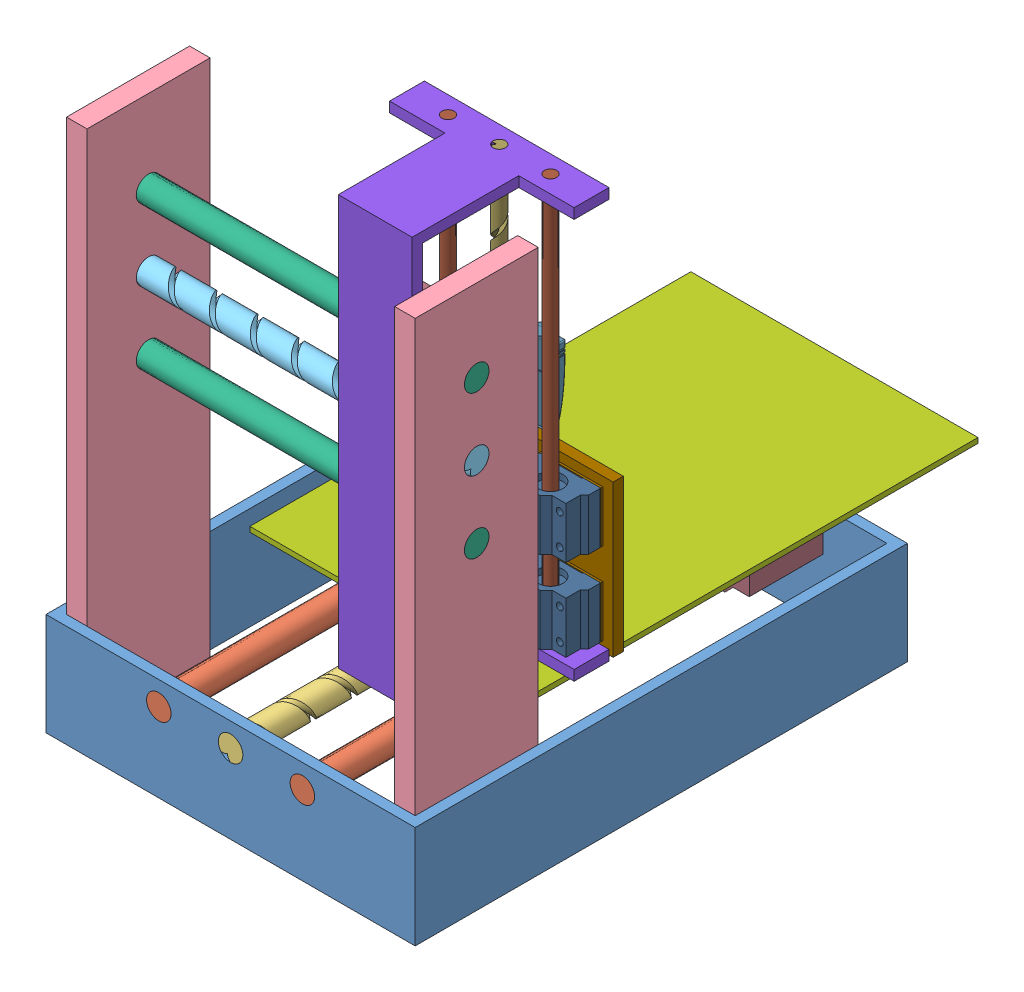
SolidWorks assembly INK Machine 2022, configuration Predeterminado. Lengths in mm.
Overall size (1205 1285 1203.26).
24 component instances, 14 part files, 60 mates.
Components (placement in the parent):
- BASE-1: BASE [Predeterminado] at (-71.4442 -39.2888 240) size (180 50 240)
- barra-1: barra [Predeterminado] at (-106.4442 -0.7888 120) x (-0.034704 -0.999398 0) z (0 0 1) size (12 12 240)
- barra-2: barra [Predeterminado] at (-36.4442 -0.7888 120) size (12 12 240)
- tornillo-1: tornillo [Predeterminado] at (-71.4442 -0.7888 60) x (-0.45507 -0.890456 0) z (0 0 1) size (12.31 12.31 1203.26)
- Viga superior-1: Viga superior [Predeterminado] at (13.5558 90.7112 325) x (0 0 1) z (-1 0 0) size (60 260 10)
- Viga superior-2: Viga superior [Predeterminado] at (-156.4442 90.7112 325) x (0 0 -1) z (1 0 0) size (60 260 10)
- tornillo2-1: tornillo2 [Predeterminado] at (13.5558 145.7112 325) x (0 0.604417 -0.796668) z (-1 0 0) size (12.31 12.31 1202.49)
- barra2-1: barra2 [Predeterminado] at (13.5558 180.7112 325) x (0 0.764966 -0.644071) z (-1 0 0) size (12 12 170)
- barra2-2: barra2 [Predeterminado] at (13.5558 110.7112 325) x (0 0.924225 0.381849) z (-1 0 0) size (12 12 170)
- cama-1: cama [Predeterminado] at (-71.4442 15.7112 143.0872) size (140 3.5 215)
- Caja superior-5: Caja superior [Predeterminado] at (-14.4442 145.7112 341.5) x (1 0 0) z (0 0 -1) size (90 200 69)
- CAMA SUPERIOR-1: CAMA SUPERIOR [Predeterminado] at (-14.4442 83.3129 275.5) x (-1 0 0) z (0 0 -1) size (90 74 6)
- SCS 6UU.stp-1: SCS 6UU.stp [Predeterminado] at (10.5558 90.8129 315) x (1 0 0) z (0 1 0) size (30 18 25)
- SCS 6UU.stp-2: SCS 6UU.stp [Predeterminado] at (10.5558 50.8129 315) x (1 0 0) z (0 1 0) size (30 18 25)
- SCS 6UU.stp-3: SCS 6UU.stp [Predeterminado] at (-39.4442 50.8129 315) x (1 0 0) z (0 1 0) size (30 18 25)
- SCS 6UU.stp-4: SCS 6UU.stp [Predeterminado] at (-39.4442 90.8129 315) x (1 0 0) z (0 1 0) size (30 18 25)
- barra3-1: barra3 [Predeterminado] at (-39.4442 45.7112 286) size (6 200 6)
- barra3-2: barra3 [Predeterminado] at (10.5558 45.7112 286) size (6 200 6)
- tornillo3-1: tornillo3 [Predeterminado] at (-14.4442 245.7112 286) x (-0.818193 0 0.574943) z (0 -1 0) size (6.16 6.16 1202.67)
- SCS12UU.stp-16: SCS12UU.stp [Predeterminado] at (-36.4442 -159.7888 125.0872) size (42 28 36)
- SCS12UU.stp-17: SCS12UU.stp [Predeterminado] at (-106.4442 -159.7888 125.0872) size (42 28 36)
- SCS12UU.stp-18: SCS12UU.stp [Predeterminado] at (3.5558 180.7112 166) x (0 -1 0) z (-1 0 0) size (42 28 36)
- SCS12UU.stp-19: SCS12UU.stp [Predeterminado] at (3.5558 110.7112 166) x (0 -1 0) z (-1 0 0) size (42 28 36)
- Reklaampastakas 1.step-2: Reklaampastakas 1.step [Predeterminado] at (-14.4442 32.6629 264.65) size (20 138.6 10.7)
Mates (geometry in assembly coordinates):
- Coincidente1: coincident aligned: plane of BASE-1 through (-161.4442 10.7112 360) normal (0 0 1); plane of tornillo-1 through (-71.4442 -0.7888 360) normal (0 0 1)
- Concéntrica7: concentric aligned: circle of BASE-1; circle of tornillo-1
- Coincidente3: coincident aligned: plane of BASE-1 through (-161.4442 10.7112 360) normal (0 0 1); plane of barra-1 through (-106.4442 -0.7888 360) normal (0 0 1)
- Concéntrica3: concentric aligned: circle of BASE-1; circle of barra-1
- Concéntrica4: concentric aligned: circle of BASE-1; circle of barra-2
- Coincidente6: coincident anti-aligned: plane of BASE-1 through (-156.4442 10.7112 125) normal (1 0 0); plane of Viga superior-2 through (-156.4442 90.7112 325) normal (-1 0 0)
- Coincidente7: coincident anti-aligned: plane of BASE-1 through (-156.4442 10.7112 355) normal (0 0 -1); plane of Viga superior-2 through (-146.4442 220.7112 355) normal (0 0 1)
- Coincidente8: coincident aligned: plane of BASE-1 through (-71.4442 -39.2888 240) normal (0 -1 0); plane of Viga superior-2 through (-146.4442 -39.2888 355) normal (0 -1 0)
- Coincidente9: coincident anti-aligned: plane of BASE-1 through (13.5558 10.7112 125) normal (-1 0 0); plane of Viga superior-1 through (13.5558 90.7112 325) normal (1 0 0)
- Coincidente10: coincident: point of BASE-1; point of Viga superior-1
- Coincidente11: coincident aligned: plane of BASE-1 through (-71.4442 -39.2888 240) normal (0 -1 0); plane of Viga superior-1 through (3.5558 -39.2888 295) normal (0 -1 0)
- Concéntrica11: concentric aligned: circle of Viga superior-1; circle of tornillo2-1
- Concéntrica10: concentric aligned: circle of Viga superior-1; circle of barra2-1
- Concéntrica12: concentric aligned: circle of Viga superior-1; circle of barra2-2
- Paralelo3: parallel anti-aligned: plane of BASE-1 through (-71.4442 -39.2888 240) normal (0 -1 0); plane of cama-1 through (-71.4442 18.2112 143.0872) normal (0 1 0)
- Coincidente26: coincident aligned: plane of BASE-1 through (-161.4442 10.7112 360) normal (0 0 1); plane of barra-2 through (-36.4442 -0.7888 360) normal (0 0 1)
- Paralelo4: parallel aligned: plane of Viga superior-1 through (13.5558 90.7112 325) normal (1 0 0); plane of barra2-1 through (13.5558 180.7112 325) normal (1 0 0)
- Coincidente29: coincident aligned: plane of Viga superior-1 through (13.5558 90.7112 325) normal (1 0 0); plane of barra2-2 through (13.5558 110.7112 325) normal (1 0 0)
- Coincidente30: coincident aligned: plane of Viga superior-1 through (13.5558 90.7112 325) normal (1 0 0); plane of barra2-1 through (13.5558 180.7112 325) normal (1 0 0)
- Coincidente31: coincident aligned: plane of Viga superior-1 through (13.5558 90.7112 325) normal (1 0 0); plane of tornillo2-1 through (13.5558 145.7112 325) normal (1 0 0)
- Paralelo9: parallel anti-aligned: plane of cama-1 through (-71.4442 18.2112 143.0872) normal (0 1 0); plane of Caja superior-5 through (-59.4442 45.7112 346.5) normal (0 -1 0)
- Tangente59: tangent anti-aligned: plane of CAMA SUPERIOR-1 through (-14.4442 83.3129 276.5) normal (0 0 1); face of SCS 6UU.stp-4
- Tangente60: tangent aligned: plane of CAMA SUPERIOR-1 through (-54.4442 115.8129 276.5) normal (-1 0 0); edge_curve of SCS 6UU.stp-4
- Tangente61: tangent aligned: plane of CAMA SUPERIOR-1 through (-54.4442 115.8129 276.5) normal (0 1 0); edge_curve of SCS 6UU.stp-4
- Tangente62: tangent anti-aligned: plane of CAMA SUPERIOR-1 through (-14.4442 83.3129 276.5) normal (0 0 1); edge_curve of SCS 6UU.stp-1
- Tangente63: tangent aligned: plane of CAMA SUPERIOR-1 through (25.5558 115.8129 276.5) normal (0 1 0); edge_curve of SCS 6UU.stp-1
- Tangente64: tangent aligned: plane of CAMA SUPERIOR-1 through (25.5558 115.8129 276.5) normal (1 0 0); edge_curve of SCS 6UU.stp-1
- Tangente65: tangent anti-aligned: plane of CAMA SUPERIOR-1 through (-14.4442 83.3129 276.5) normal (0 0 1); edge_curve of SCS 6UU.stp-2
- Tangente66: tangent aligned: plane of CAMA SUPERIOR-1 through (25.5558 75.8129 276.5) normal (0 1 0); edge_curve of SCS 6UU.stp-2
- Tangente67: tangent aligned: plane of CAMA SUPERIOR-1 through (25.5558 50.8129 276.5) normal (1 0 0); edge_curve of SCS 6UU.stp-2
- Tangente68: tangent anti-aligned: plane of CAMA SUPERIOR-1 through (-14.4442 83.3129 276.5) normal (0 0 1); edge_curve of SCS 6UU.stp-3
- Tangente69: tangent aligned: plane of CAMA SUPERIOR-1 through (-54.4442 75.8129 276.5) normal (0 1 0); edge_curve of SCS 6UU.stp-3
- Tangente70: tangent aligned: plane of CAMA SUPERIOR-1 through (-54.4442 50.8129 276.5) normal (-1 0 0); edge_curve of SCS 6UU.stp-3
- Concéntrica27: concentric anti-aligned: circle of Caja superior-5; circle of barra3-2
- Coincidente40: coincident aligned: plane of Caja superior-5 through (-59.4442 245.7112 346.5) normal (0 1 0); plane of barra3-2 through (10.5558 245.7112 286) normal (0 1 0)
- Concéntrica28: concentric anti-aligned: circle of Caja superior-5; circle of barra3-1
- Coincidente41: coincident aligned: plane of Caja superior-5 through (-59.4442 245.7112 346.5) normal (0 1 0); plane of barra3-1 through (-39.4442 245.7112 286) normal (0 1 0)
- Coincidente42: coincident aligned: plane of Caja superior-5 through (-59.4442 245.7112 346.5) normal (0 1 0); plane of tornillo3-1 through (-14.4442 245.7112 286) normal (0 1 0)
- Concéntrica29: concentric aligned: circle of Caja superior-5; circle of tornillo3-1
- Paralelo12: parallel aligned: plane of Viga superior-1 through (13.5558 90.7112 325) normal (1 0 0); plane of CAMA SUPERIOR-1 through (30.5558 46.3129 270.5) normal (1 0 0)
- Concéntrica31: concentric aligned: circle of SCS 6UU.stp-1; circle of barra3-2
- Concéntrica32: concentric anti-aligned: cylinder of SCS 6UU.stp-4; cylinder of barra3-1 through (-39.4442 245.7112 286) axis (0 -1 0) radius 3
- Tangente75: tangent anti-aligned: plane of cama-1 through (-71.4442 14.7112 143.0872) normal (0 -1 0); edge_curve of SCS12UU.stp-16
- Tangente76: tangent aligned: plane of cama-1 through (-15.4442 14.7112 125.0872) normal (1 0 0); edge_curve of SCS12UU.stp-16
- Tangente77: tangent aligned: plane of cama-1 through (-15.4442 14.7112 125.0872) normal (0 0 -1); edge_curve of SCS12UU.stp-16
- Tangente78: tangent anti-aligned: plane of cama-1 through (-71.4442 14.7112 143.0872) normal (0 -1 0); edge_curve of SCS12UU.stp-17
- Tangente79: tangent aligned: plane of cama-1 through (-127.4442 14.7112 125.0872) normal (0 0 -1); edge_curve of SCS12UU.stp-17
- Concéntrica33: concentric anti-aligned: cylinder of barra-1 through (-106.4442 -0.7888 360) axis (0 0 -1) radius 6; circle of SCS12UU.stp-17
- Tangente81: tangent anti-aligned: plane of Caja superior-5 through (-14.4442 145.7112 340.5) normal (0 0 -1); edge_curve of SCS12UU.stp-18
- Concéntrica34: concentric anti-aligned: cylinder of barra2-1 through (-156.4442 180.7112 325) axis (1 0 0) radius 6; circle of SCS12UU.stp-18
- Tangente84: tangent aligned: plane of Caja superior-5 through (3.5558 131.7112 340.5) normal (1 0 0); edge_curve of SCS12UU.stp-18
- Tangente85: tangent aligned: plane of Caja superior-5 through (-32.4442 159.7112 340.5) normal (0 -1 0); edge_curve of SCS12UU.stp-18
- Tangente86: tangent anti-aligned: plane of Caja superior-5 through (-14.4442 145.7112 340.5) normal (0 0 -1); edge_curve of SCS12UU.stp-19
- Concéntrica35: concentric anti-aligned: cylinder of barra2-2 through (-156.4442 110.7112 325) axis (1 0 0) radius 6; circle of SCS12UU.stp-19
- Tangente87: tangent aligned: plane of Caja superior-5 through (3.5558 131.7112 340.5) normal (1 0 0); edge_curve of SCS12UU.stp-19
- Tangente88: tangent aligned: plane of Caja superior-5 through (-32.4442 131.7112 340.5) normal (0 1 0); edge_curve of SCS12UU.stp-19
- Coincidente51: coincident anti-aligned: plane of CAMA SUPERIOR-1 through (-14.4442 83.3129 270.5) normal (0 0 -1); plane of Reklaampastakas 1.step-2 through (-14.4442 32.6629 270.5) normal (0 0 1)
- Coincidente52: coincident aligned: plane of CAMA SUPERIOR-1 through (30.5558 120.3129 270.5) normal (0 1 0); plane of Reklaampastakas 1.step-2 through (-4.4442 120.3129 270.5) normal (0 1 0)
- Distancia1: distance = 35 mm aligned: plane of CAMA SUPERIOR-1 through (30.5558 46.3129 270.5) normal (1 0 0); plane of Reklaampastakas 1.step-2 through (-4.4442 40.3129 270.5) normal (1 0 0)
- Tangente90: tangent anti-aligned: plane of Viga superior-1 through (3.5558 90.7112 325) normal (-1 0 0); edge_curve of SCS12UU.stp-18
